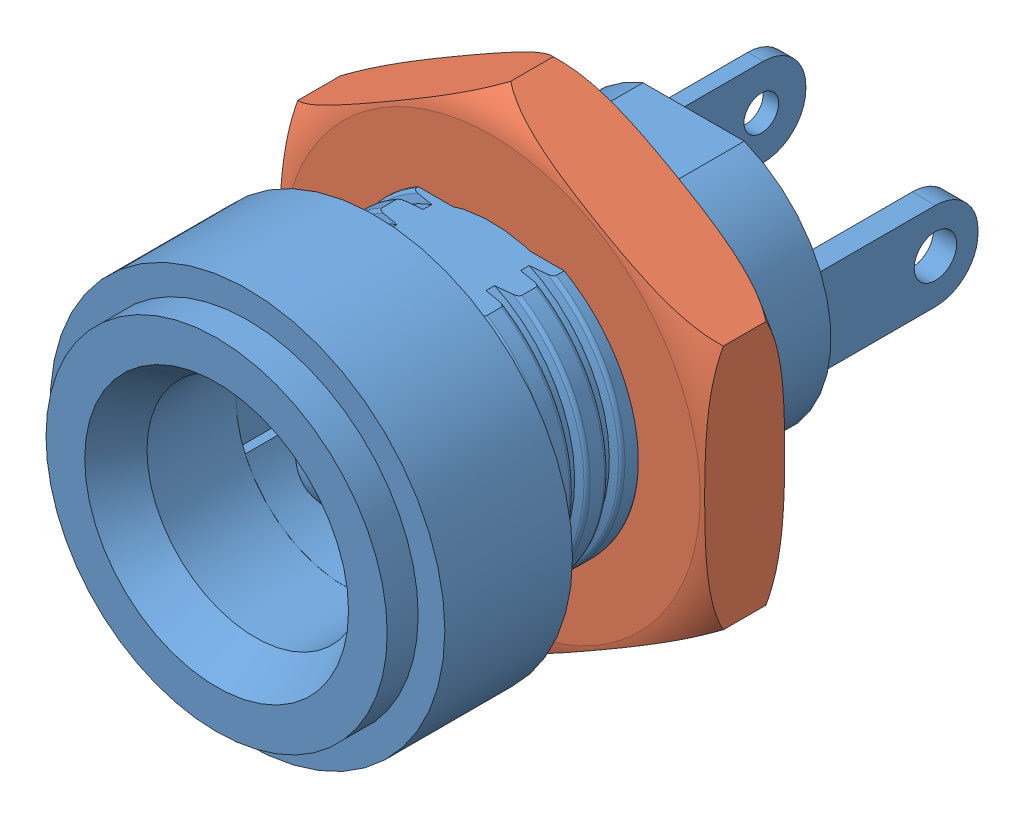
SolidWorks assembly DC Jack Panel Mount ASSY, configuration Default. Lengths in mm.
Overall size (16.5 15.88 17.63).
2 component instances, 2 part files, 3 mates.
Components (placement in the parent):
- DC Jack Panel Mount Base-1: DC Jack Panel Mount Base [Default] at origin size (10.2 10.2 17.63)
- DC Jack Panel Mount Nut-1: DC Jack Panel Mount Nut [Default] at (0 0 -7.35) x (0.866025 -0.5 0) z (0 0 1) size (12.7 11 2.1)
Mates (geometry in assembly coordinates):
- Concentric1: concentric: cylinder of DC Jack Panel Mount Base-1 through (0 0 0) axis (0 0 1) radius 5.1; cylinder of DC Jack Panel Mount Nut-1 through (0 -1.2484 0.997) axis (0 0 1) radius 3.4544
- Distance1: distance = 3 mm: plane of DC Jack Panel Mount Nut-1 through (0 0 -6.3) normal (0 0 1); plane of DC Jack Panel Mount Base-1 through (5.1 0 -3.3) normal (0 0 -1)
- Parallel1: parallel: plane of DC Jack Panel Mount Nut-1 through (5.5 -3.1754 -6.3) normal (1 0 0); plane of assembly
